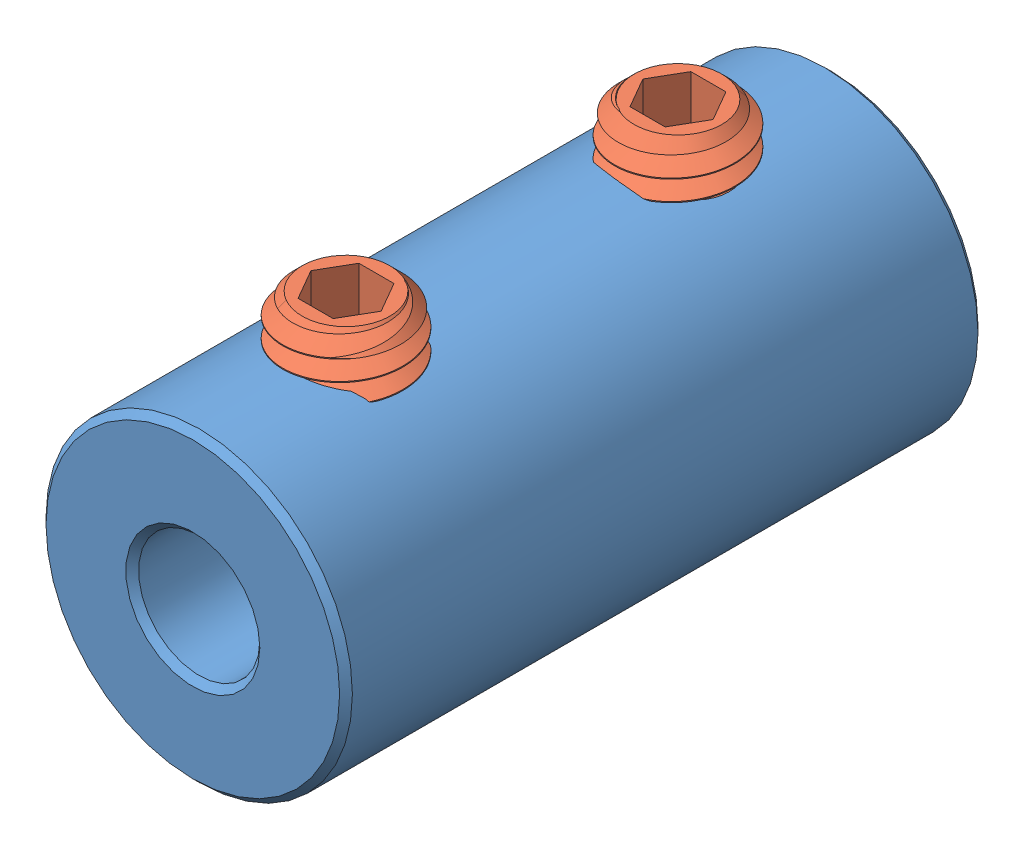
SolidWorks assembly Tetrix Coupler (Axle to Axle), configuration Default. Lengths in mm.
Overall size (12 13.92 25).
3 component instances, 2 part files, 0 mates.
Components (placement in the parent):
- Tetrix Coupler (Axle to Axle) Body-1: Tetrix Coupler (Axle to Axle) Body [Default] at origin size (12 12 25)
- Tetrix Coupler (Axle to Axle) Set Screw-1: Tetrix Coupler (Axle to Axle) Set Screw [Default] at (0 2.375 6.5) x (0.866025 0 0.5) z (-0.5 0 0.866025) size (4.78 5.54 4.7)
- Tetrix Coupler (Axle to Axle) Set Screw-2: Tetrix Coupler (Axle to Axle) Set Screw [Default] at (0 2.375 -6.5) x (-0.866025 0 -0.5) z (0.5 0 -0.866025) size (4.78 5.54 4.7)
